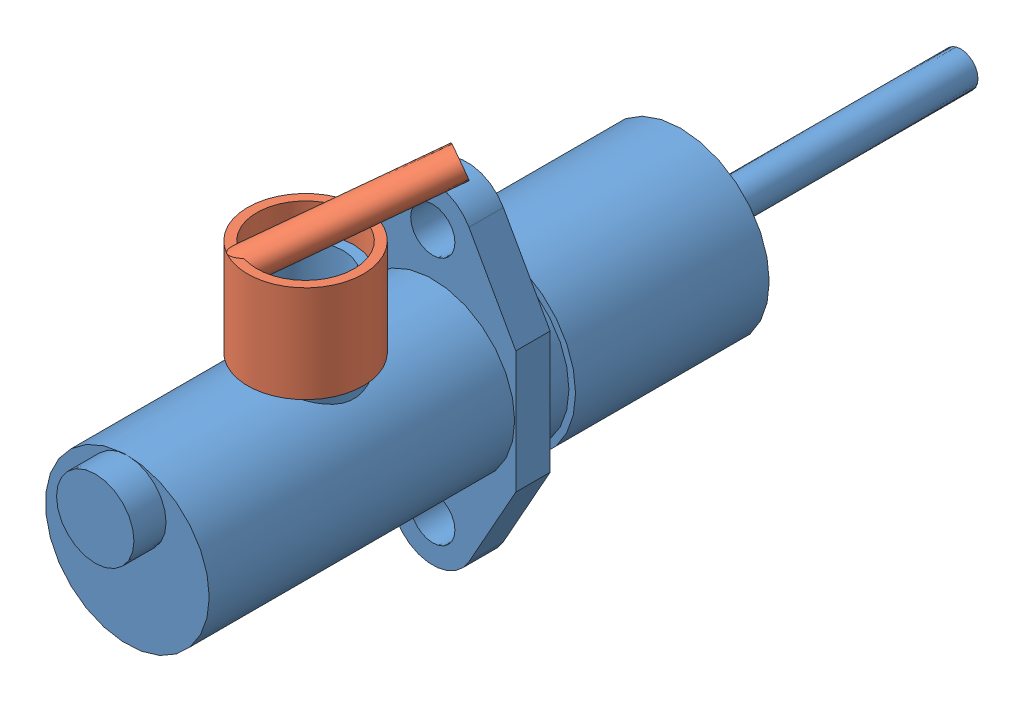
SolidWorks assembly Master Cylinder, configuration Default. Lengths in mm.
Overall size (45.21 93.02 198.63).
2 component instances, 2 part files, 2 mates.
Components (placement in the parent):
- Cylinder-1: Cylinder [Default] at (41.4952 115.1749 175.835) size (40.64 76.2 198.63)
- Reservoir Inlet-1: Reservoir Inlet [Default] at (41.4952 133.9709 212.919) x (-0.872735 0 -0.488193) z (0.488193 0 -0.872735) size (26.54 36.12 40.53)
Mates (geometry in assembly coordinates):
- Concentric1: concentric aligned: circle of Cylinder-1; circle of Reservoir Inlet-1
- Tangent1: tangent anti-aligned: cylinder of Cylinder-1 through (41.4952 115.1749 171.263) axis (0 0 1) radius 18.796; plane of Reservoir Inlet-1 through (41.4952 133.9709 212.919) normal (0 -1 0)
